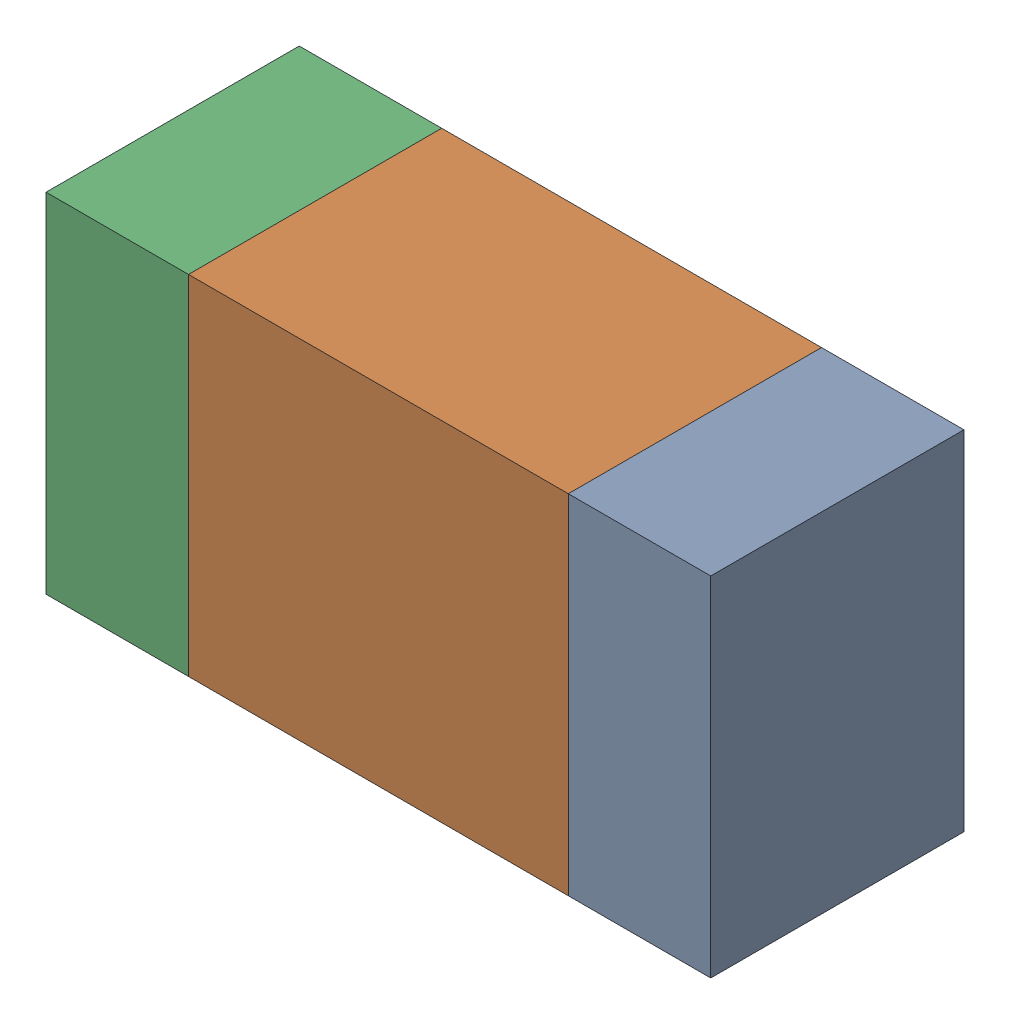
SolidWorks assembly R115_2PCB, configuration Default. Lengths in mm.
Overall size (1.05 0.55 0.4).
6 component instances, 2 part files, 0 mates.
Components (placement in the parent):
- 854785432-1: 854785432 [Default] at (112.8124 99.9999 0) size (0.22 0.55 0.4)
  - Extruded-1: Extruded [Default] at origin size (0.22 0.55 0.4)
- 854785568-1: 854785568 [Default] at (112.3999 99.9999 0) size (0.6 0.55 0.4)
  - Extruded_2-1: Extruded_2 [Default] at origin size (0.6 0.55 0.4)
- 854785432-2: 854785432 [Default] at (111.9874 99.9999 0) size (0.22 0.55 0.4)
  - Extruded-1: Extruded [Default] at origin size (0.22 0.55 0.4)
